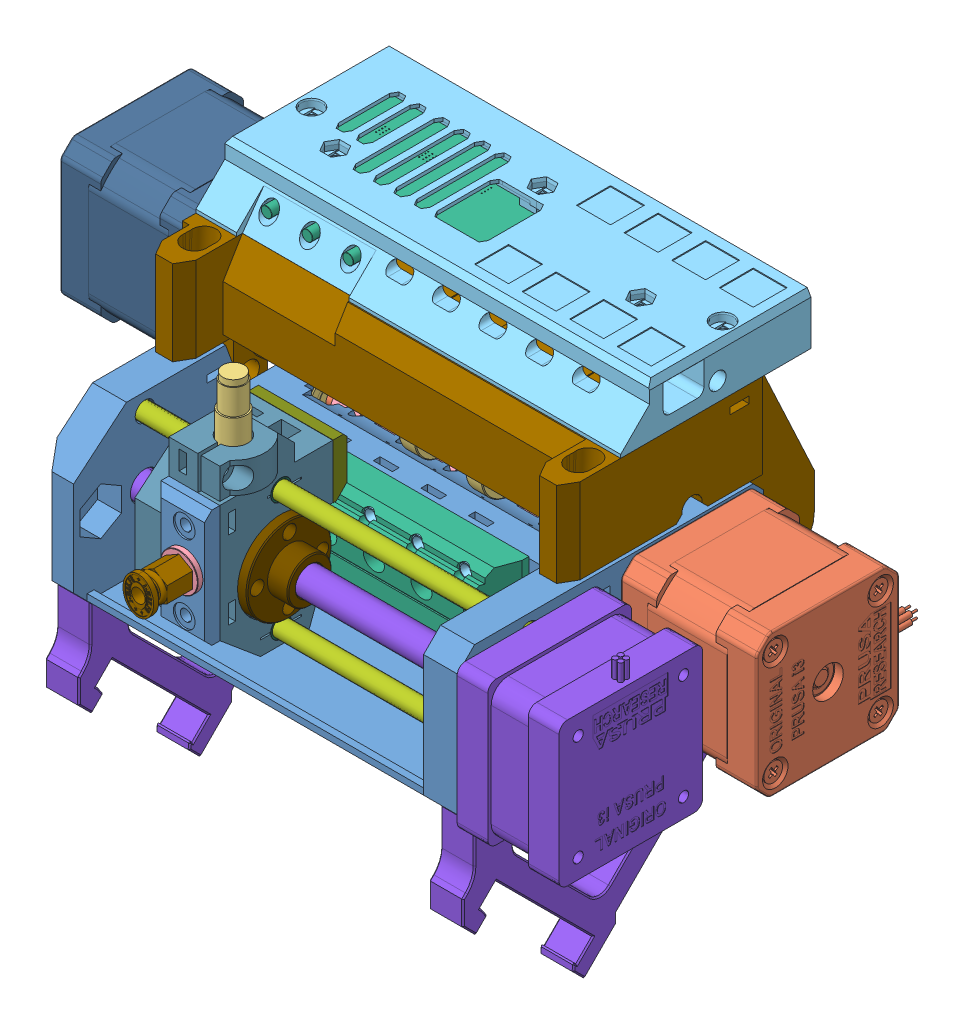
SolidWorks assembly MMU2 Unit Assembly, configuration Default. Lengths in mm.
Overall size (205 144.81 125.03).
60 component instances, 27 part files, 25 mates.
Components (placement in the parent):
- MMU2 Pulley Body Assembly-1: MMU2 Pulley Body Assembly [Default] at (-17.1636 1.806 40.3732) size (163 48.15 110.15)
  - mmu2-pulley-body(M1)-1: mmu2-pulley-body(M1) [Default] at (5.8785 74.1609 77.9167) x (1 0 0) z (0 1 0) size (123 110 46)
  - Pulley Motor-1: Pulley Motor [NEMA 17 Stepper] at (141.8785 73.6609 77.9167) x (0 -1 0) z (0 0 -1) size (42.3 150 51.35)
  - 625 Bearing-1: 625 Bearing [6153K15] at (-5.6215 73.6609 77.9167) x (0 -0.100672 -0.99492) z (1 0 0) size (16 16 5)
  - Extruder Pulley-1: Extruder Pulley [Default] at (106.1795 -192.3915 231.3649) x (0 0.91085 0.412738) z (-1 0 0) size (9.1 8.2 13)
  - Extruder Pulley-9: Extruder Pulley [Default] at (78.1795 -192.3915 231.3649) x (0 0.91085 0.412738) z (-1 0 0) size (9.1 8.2 13)
  - Extruder Pulley-10: Extruder Pulley [Default] at (64.1795 -192.3915 231.3649) x (0 0.91085 0.412738) z (-1 0 0) size (9.1 8.2 13)
  - Extruder Pulley-11: Extruder Pulley [Default] at (92.1795 -192.3915 231.3649) x (0 0.91085 0.412738) z (-1 0 0) size (9.1 8.2 13)
  - Extruder Pulley-12: Extruder Pulley [Default] at (50.1785 -192.3915 231.3649) x (0 0.91085 0.412738) z (-1 0 0) size (9.1 8.2 13)
  - PTFE 4x2x19-1: PTFE 4x2x19 [Default] at (8.8785 78.1609 107.4167) x (1 0 0) z (0 1 0) size (4 19 4)
  - PTFE 4x2x19-2: PTFE 4x2x19 [Default] at (22.8785 78.1609 107.4167) x (0.418318 0.908301 0) z (-0.908301 0.418318 0) size (4 19 4)
  - PTFE 4x2x19-3: PTFE 4x2x19 [Default] at (36.8785 78.1609 107.4167) x (1 0 0) z (0 1 0) size (4 19 4)
  - PTFE 4x2x19-4: PTFE 4x2x19 [Default] at (50.8785 78.1609 107.4167) x (1 0 0) z (0 1 0) size (4 19 4)
  - PTFE 4x2x19-5: PTFE 4x2x19 [Default] at (64.8785 78.1609 107.4167) x (1 0 0) z (0 1 0) size (4 19 4)
  - mmu2-front-PTFE-holder(M1)-1: mmu2-front-PTFE-holder(M1) [Default] at (5.8785 74.1609 82.9167) x (1 0 0) z (0 1 0) size (84 15 22.5)
  - Smooth Rod 5x120sh-1: Smooth Rod 5x120sh [Default] at (41.8785 55.1609 125.9167) x (0 0 -1) z (1 0 0) size (5 5 120)
  - Smooth Rod 5x120sh-2: Smooth Rod 5x120sh [Default] at (41.8785 90.1609 125.9167) x (0 0.926511 -0.376267) z (1 0 0) size (5 5 120)
  - Selector Motor-1: Selector Motor [Default] at (116.8785 71.1609 125.9167) x (0 1 0) z (-1 0 0) size (47.3 42.3 150)
  - 625 Bearing-2: 625 Bearing [6153K15] at (-10.1215 74.1609 47.9167) x (0 0 -1) z (1 0 0) size (16 16 5)
  - 625 Bearing-3: 625 Bearing [6153K15] at (83.8785 74.1609 47.9167) x (0 -0.091081 -0.995843) z (1 0 0) size (16 16 5)
- MMU2 Idler Assembly-1: MMU2 Idler Assembly [Default] at (63.1009 170.9903 25.4645) x (-1 0 0) z (0 0 1) size (165 58.02 78.33)
  - mmu2-idler-body(M1)-1: mmu2-idler-body(M1) [Default] at (74.386 71.0234 92.8254) x (-1 0 0) z (0 -1 0) size (125 78.33 58.02)
  - NEMA-17 40mm PR-1: NEMA-17 40mm PR [По умолчанию] at (143.386 71.0234 92.8254) x (0 0 -1) z (0 1 0) size (42.3 62 51.35)
  - MMU2 Idler Shaft Assembly-1: MMU2 Idler Shaft Assembly [Default] at (81.8402 44.4461 182.585) x (-1 0 0) z (0 -0.405266 -0.914199) size (95 39.64 31.09)
    - mmu2-idler(M1)-1: mmu2-idler(M1) [Default] at (7.4542 60.6735 71.2872) size (95 34 28)
    - 5x16 Shaft-1: 5x16 Shaft [Default] at (66.4542 72.4912 69.2035) x (0 0 -1) z (1 0 0) size (5 5 16)
    - 625 Bearing-1: 625 Bearing [6153K15] at (66.4542 72.4912 69.2035) x (0 0 -1) z (1 0 0) size (16 16 5)
    - 625 Bearing-2: 625 Bearing [6153K15] at (52.4542 68.3869 62.0947) x (0 0 -1) z (1 0 0) size (16 16 5)
    - 625 Bearing-3: 625 Bearing [6153K15] at (38.4542 60.6735 59.2872) x (0 0 -1) z (1 0 0) size (16 16 5)
    - 625 Bearing-4: 625 Bearing [6153K15] at (24.4542 52.96 62.0947) x (0 0 -1) z (1 0 0) size (16 16 5)
    - 625 Bearing-5: 625 Bearing [6153K15] at (10.4542 48.8558 69.2035) x (0 0 -1) z (1 0 0) size (16 16 5)
    - 625 Bearing-6: 625 Bearing [6153K15] at (74.9542 60.6735 71.2872) x (0 0 -1) z (1 0 0) size (16 16 5)
    - 5x16 Shaft-2: 5x16 Shaft [Default] at (52.4542 68.3869 62.0947) x (0 0 -1) z (1 0 0) size (5 5 16)
    - 5x16 Shaft-3: 5x16 Shaft [Default] at (38.4542 60.6735 59.2872) x (0 0 -1) z (1 0 0) size (5 5 16)
    - 5x16 Shaft-4: 5x16 Shaft [Default] at (24.4542 52.96 62.0947) x (0 0 -1) z (1 0 0) size (5 5 16)
    - 5x16 Shaft-5: 5x16 Shaft [Default] at (10.4542 48.8558 69.2035) x (0 0 -1) z (1 0 0) size (5 5 16)
    - M3-10 Screw-1: M3-10 Screw [93235A313] at (-12.5458 62.726 72.4723) x (0.999493 -0.015924 0.027582) z (0 -0.866025 -0.5) size (5.5 5.5 13.21)
    - M3-10 Screw-2: M3-10 Screw [93235A313] at (-2.5458 62.726 72.4723) x (0.596164 -0.401431 0.6953) z (0 -0.866025 -0.5) size (5.5 5.5 13.21)
  - 5x16 Shaft-1: 5x16 Shaft [Default] at (1.886 71.0234 92.8254) x (0 0.20462 -0.978842) z (1 0 0) size (5 5 16)
  - M3-10 Screw-1: M3-10 Screw [93235A313] at (-9.114 59.0234 92.8254) x (0.999809 0 0.019535) z (0 -1 0) size (5.5 5.5 13.21)
- 5x16 Shaft-1: 5x16 Shaft [Default] at (-32.2851 75.967 88.2899) x (0 0 -1) z (1 0 0) size (5 5 16)
- 5x16 Shaft-2: 5x16 Shaft [Default] at (71.7149 75.967 88.2899) x (0 0 -1) z (1 0 0) size (5 5 16)
- MMU2 finda Selector-1: MMU2 finda Selector [Default] at (-7.8064 34.8231 200.457) x (0.998423 0.056139 0) z (-0.056139 0.998423 0) size (35.3 43.62 71.45)
  - mmu2-selector-finda(M1)-1: mmu2-selector-finda(M1) [Default] at (-43.0577 77.1671 43.6299) x (0.998423 0 -0.056139) z (0.056139 0 0.998423) size (28.2 33.25 54.5)
  - Tube 5x6x25bt-1: Tube 5x6x25bt [Default] at (8.2929 34.1671 21.7125) x (0 1 0) z (0.056139 0 0.998423) size (6 25 6)
  - Tube 5x6x25bt-2: Tube 5x6x25bt [Default] at (10.2578 34.1671 56.6573) x (0.033082 0.807928 0.588351) z (0.045357 -0.589281 0.806654) size (6 25 6)
  - mmu2-blade-holder-1: mmu2-blade-holder [Default] at (-43.0577 77.5171 43.6299) x (0.998423 0 -0.056139) z (0 1 0) size (25 16 4)
  - Blade-1: Blade [Default] at (71.6227 49.0171 -0.7074) x (0.973506 0 -0.228661) z (0.228661 0 0.973506) size (15.94 0.5 8.9)
  - Z_NUT-1: Z_NUT [Default] at (20.1738 34.1671 37.0697) x (0 1 0) z (0.056139 0 0.998423) size (25 10 25)
  - mmu2-selector-front-plate-1: mmu2-selector-front-plate [Default] at (-43.0577 77.1671 43.6299) x (0.998423 0 -0.056139) z (0 -1 0) size (15 34.5 4.5)
  - finda Ball-1: finda Ball [Default] at (16.2703 26.1671 47.8058) x (-0.163464 -0.986507 0.009191) z (-0.984951 0.163722 0.055382) size (8 8 8)
  - PINDA Probe-1: PINDA Probe [Default] at (17.874 26.1671 76.327) x (-0.434988 -0.900104 0.024458) z (-0.056139 0 -0.998423) size (7.8 7.8 35.75)
  - M5 Pressfit Nut-1: M5 Pressfit Nut [94100A140] at (16.0738 10.1671 44.3113) x (0 0 1) z (0 -1 0) size (11 11 5.08)
- MMU2 Ele Assembly-1: MMU2 Ele Assembly [Default] at (-11.3146 194.3638 215.0737) x (1 0 0) z (0 0 -1) size (125 17.41 56)
  - mmu2-ele-cover(M1)-1: mmu2-ele-cover(M1) [Default] at (0.0295 94.3969 96.7837) x (1 0 0) z (0 -1 0) size (125 56 15)
  - MM-control-1: MM-control [Default] at (86.0295 60.3969 85.7837) x (-1 0 0) z (0 1 0) size (107.3 50.26 15.75)
- mmu2-rear-PTFE-holder(M1)-1: mmu2-rear-PTFE-holder(M1) [Default] at (-11.2851 75.967 118.2899) x (1 0 0) z (0 1 0) size (64.6 20.8 5.7)
- mmu2-frame-holder-1: mmu2-frame-holder [Default] at (-33.2851 33.4957 175.926) x (-1 0 0) z (0 0.707107 -0.707107) size (10 62.1 79.76)
- mmu2-frame-holder-2: mmu2-frame-holder [Default] at (79.7149 33.4957 175.926) x (-1 0 0) z (0 0.707107 -0.707107) size (10 62.1 79.76)
- M5 Pushfit Bowden Connector-1: M5 Pushfit Bowden Connector [Default] at (5.2288 80.3642 129.275) x (0 1 0) z (1 0 0) size (11.88 18.68 9.85)
Mates (geometry in assembly coordinates):
- Concentric1: concentric aligned: cylinder of MMU2 Pulley Body Assembly-1/625 Bearing-3 through (69.2149 75.967 88.2899) axis (1 0 0) radius 2.5; cylinder of MMU2 Idler Assembly-1/mmu2-idler-body(M1)-1 through (68.7149 75.967 88.2899) axis (1 0 0) radius 2.55
- Coincident1: coincident anti-aligned: plane of MMU2 Pulley Body Assembly-1/mmu2-pulley-body(M1)-1 through (19.7149 75.967 118.2899) normal (-1 0 0); plane of MMU2 Idler Assembly-1/mmu2-idler-body(M1)-1 through (19.7149 99.967 118.2899) normal (1 0 0)
- Concentric2: concentric anti-aligned: cylinder of MMU2 Idler Assembly-1/mmu2-idler-body(M1)-1 through (-41.2851 75.967 88.2899) axis (1 0 0) radius 2.55; cylinder of 5x16 Shaft-1 through (-24.2851 75.967 88.2899) axis (-1 0 0) radius 2.5
- Coincident2: coincident aligned: plane of MMU2 Idler Assembly-1/mmu2-idler-body(M1)-1 through (-40.2851 75.967 97.2899) normal (-1 0 0); plane of 5x16 Shaft-1 through (-40.2851 75.967 88.2899) normal (-1 0 0)
- Concentric3: concentric anti-aligned: cylinder of MMU2 Idler Assembly-1/mmu2-idler-body(M1)-1 through (68.7149 75.967 88.2899) axis (1 0 0) radius 2.55; cylinder of 5x16 Shaft-2 through (79.7149 75.967 88.2899) axis (-1 0 0) radius 2.5
- Coincident3: coincident aligned: plane of MMU2 Idler Assembly-1/mmu2-idler-body(M1)-1 through (79.7149 75.967 97.2899) normal (1 0 0); plane of 5x16 Shaft-2 through (79.7149 75.967 88.2899) normal (1 0 0)
- Parallel1: parallel aligned: plane of MMU2 Pulley Body Assembly-1/mmu2-pulley-body(M1)-1 through (74.7149 96.967 187.2899) normal (0 1 0); plane of MMU2 Idler Assembly-1/mmu2-idler-body(M1)-1 through (-40.2851 122.967 143.2899) normal (0 1 0)
- Concentric5: concentric anti-aligned: cylinder of MMU2 Pulley Body Assembly-1/Smooth Rod 5x120sh-2 through (84.7149 91.967 166.2899) axis (-1 0 0) radius 2.5; cylinder of MMU2 finda Selector-1/Tube 5x6x25bt-2 through (-25.7851 91.967 166.2899) axis (1 0 0) radius 2.5
- LimitDistance1: limit distance = 62.4605 mm anti-aligned: plane of MMU2 finda Selector-1/Z_NUT-1 through (20.2544 72.967 166.2899) normal (1 0 0); plane of MMU2 Pulley Body Assembly-1/Selector Motor-1 through (82.7149 72.967 166.2899) normal (-1 0 0)
- Concentric6: concentric aligned: cylinder of MMU2 Idler Assembly-1/mmu2-idler-body(M1)-1 through (-35.2851 109.967 110.2899) axis (0 1 0) radius 1.65; cylinder of MMU2 Ele Assembly-1/mmu2-ele-cover(M1)-1 through (-35.2851 109.967 110.2899) axis (0 1 0) radius 1.65
- Concentric7: concentric aligned: cylinder of MMU2 Idler Assembly-1/mmu2-idler-body(M1)-1 through (79.7149 109.967 104.2899) axis (0 1 0) radius 1.65; cylinder of MMU2 Ele Assembly-1/mmu2-ele-cover(M1)-1 through (79.7149 109.967 104.2899) axis (0 1 0) radius 1.65
- Coincident5: coincident anti-aligned: plane of MMU2 Idler Assembly-1/mmu2-idler-body(M1)-1 through (-40.2851 122.967 143.2899) normal (0 1 0); plane of MMU2 Ele Assembly-1/mmu2-ele-cover(M1)-1 through (-40.2851 122.967 139.2899) normal (0 -1 0)
- Concentric8: concentric aligned: cylinder of MMU2 Pulley Body Assembly-1/mmu2-pulley-body(M1)-1 through (-1.2851 45.967 104.2899) axis (0 0.939693 -0.34202) radius 1.7; cylinder of mmu2-rear-PTFE-holder(M1)-1 through (-1.2851 45.967 104.2899) axis (0 0.939693 -0.34202) radius 1.7
- Concentric9: concentric aligned: cylinder of MMU2 Pulley Body Assembly-1/mmu2-pulley-body(M1)-1 through (40.7149 45.967 104.2899) axis (0 0.939693 -0.34202) radius 1.7; cylinder of mmu2-rear-PTFE-holder(M1)-1 through (40.7149 45.967 104.2899) axis (0 0.939693 -0.34202) radius 1.7
- Coincident6: coincident anti-aligned: plane of MMU2 Pulley Body Assembly-1/mmu2-pulley-body(M1)-1 through (-13.2851 80.967 103.2899) normal (0 0.984808 -0.173648); plane of mmu2-rear-PTFE-holder(M1)-1 through (-13.2851 80.967 103.2899) normal (0 -0.984808 0.173648)
- Coincident7: coincident anti-aligned: plane of MMU2 Pulley Body Assembly-1/mmu2-pulley-body(M1)-1 through (-38.2851 50.967 183.2899) normal (0 -1 0); plane of mmu2-frame-holder-1 through (-38.2851 50.967 182.2899) normal (0 1 0)
- Coincident8: coincident anti-aligned: plane of MMU2 Pulley Body Assembly-1/mmu2-pulley-body(M1)-1 through (-38.2851 50.967 183.2899) normal (0 -1 0); plane of mmu2-frame-holder-2 through (74.7149 50.967 182.2899) normal (0 1 0)
- Concentric10: concentric aligned: cylinder of MMU2 Pulley Body Assembly-1/mmu2-pulley-body(M1)-1 through (79.7149 49.967 111.2899) axis (0 1 0) radius 1.65; cylinder of mmu2-frame-holder-2 through (79.7149 -6.8462 111.2899) axis (0 1 0) radius 3.25
- Concentric11: concentric aligned: cylinder of MMU2 Pulley Body Assembly-1/mmu2-pulley-body(M1)-1 through (79.7149 49.967 175.2899) axis (0 1 0) radius 1.65; cylinder of mmu2-frame-holder-2 through (79.7149 -6.8462 175.2899) axis (0 1 0) radius 3.25
- Concentric12: concentric aligned: cylinder of MMU2 Pulley Body Assembly-1/mmu2-pulley-body(M1)-1 through (-33.2851 49.967 111.2899) axis (0 1 0) radius 1.65; cylinder of mmu2-frame-holder-1 through (-33.2851 -6.8462 111.2899) axis (0 1 0) radius 3.25
- Concentric13: concentric aligned: cylinder of MMU2 Pulley Body Assembly-1/mmu2-pulley-body(M1)-1 through (-33.2851 49.967 175.2899) axis (0 1 0) radius 1.65; cylinder of mmu2-frame-holder-1 through (-33.2851 -6.8462 175.2899) axis (0 1 0) radius 3.25
- Concentric14: concentric anti-aligned: cylinder of MMU2 Pulley Body Assembly-1/Selector Motor-1 through (84.7149 72.967 166.2899) axis (-1 0 0) radius 4; cylinder of MMU2 finda Selector-1/Z_NUT-1 through (-2.7851 72.967 166.2899) axis (1 0 0) radius 6.5
- Concentric15: concentric: cylinder of MMU2 finda Selector-1/M5 Pressfit Nut-1 through (5.7544 79.967 187.2899) axis (0 0 1) radius 5.5; cylinder of M5 Pushfit Bowden Connector-1 through (5.7544 79.967 197.7899) axis (0 0 -1) radius 1.7821
- Coincident9: coincident: plane of MMU2 finda Selector-1/M5 Pressfit Nut-1 through (5.7544 79.967 190.2899) normal (0 0 1); plane of M5 Pushfit Bowden Connector-1 through (5.7544 79.967 190.2899) normal (0 0 1)
- Parallel2: parallel anti-aligned: plane of MMU2 finda Selector-1/mmu2-selector-front-plate-1 through (11.7544 62.467 188.7899) normal (1 0 0); plane of M5 Pushfit Bowden Connector-1 through (9.7544 77.6576 197.7899) normal (-1 0 0)
